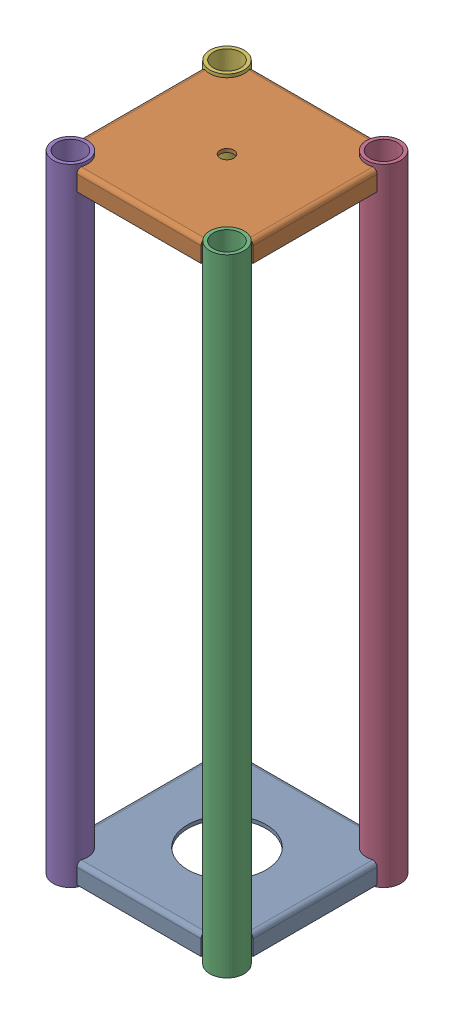
SolidWorks assembly GE-25202, configuration Default. Lengths in mm.
Overall size (185.8 609.6 185.8).
6 component instances, 3 part files, 17 mates.
Components (placement in the parent):
- GE-25202-01-1: GE-25202-01 [Default] at (0 22.225 0) size (171.42 19.05 171.42)
- GE-25202-02-1: GE-25202-02 [Default] at (0 606.425 0) size (171.42 19.05 171.42)
- GE-25202-03-1: GE-25202-03 [Default] at (76.2 0 76.2) size (33.4 609.6 33.4)
- GE-25202-03-2: GE-25202-03 [Default] at (76.2 0 -76.2) size (33.4 609.6 33.4)
- GE-25202-03-3: GE-25202-03 [Default] at (-76.2 0 76.2) size (33.4 609.6 33.4)
- GE-25202-03-4: GE-25202-03 [Default] at (-76.2 0 -76.2) size (33.4 609.6 33.4)
Mates (geometry in assembly coordinates):
- Coincident1: coincident aligned: plane of shortie_m6-01-1 through (0 22.225 0) normal (0 0 1)
- Coincident2: coincident aligned: plane of shortie_m6-01-1 through (0 22.225 0) normal (1 0 0)
- Coincident3: coincident aligned: plane of shortie_m6-01-1 through (0 22.225 85.7123) normal (0 0 1); plane of shortie_m6-02-1 through (0 606.425 85.7123) normal (0 0 1)
- Coincident4: coincident aligned: plane of shortie_m6-01-1 through (85.7123 22.225 0) normal (1 0 0); plane of shortie_m6-02-1 through (85.7123 606.425 0) normal (1 0 0)
- Distance1: distance = 603.25 mm anti-aligned: plane of shortie_m6-02-1 through (76.2 606.425 76.2) normal (0 1 0); plane of shortie_m6-01-1 through (-60.3828 3.175 85.7123) normal (0 -1 0)
- Concentric1: concentric anti-aligned: cylinder of shortie_m6-02-1 through (-76.2 603.0087 76.2) axis (0 1 0) radius 16.7005; cylinder of shortie_m6-03-3 through (-76.2 609.6 76.2) axis (0 -1 0) radius 16.7005
- Distance2: distance = 3.175 mm aligned: plane of shortie_m6-03-3 through (-76.2 609.6 76.2) normal (0 1 0); plane of shortie_m6-02-1 through (76.2 606.425 76.2) normal (0 1 0)
- Concentric2: concentric anti-aligned: cylinder of shortie_m6-02-1 through (76.2 603.0087 76.2) axis (0 1 0) radius 16.7005; cylinder of shortie_m6-03-1 through (76.2 609.6 76.2) axis (0 -1 0) radius 16.7005
- Coincident7: coincident aligned: plane of shortie_m6-03-1 through (76.2 609.6 76.2) normal (0 1 0); plane of shortie_m6-03-3 through (-76.2 609.6 76.2) normal (0 1 0)
- Concentric3: concentric anti-aligned: cylinder of shortie_m6-02-1 through (76.2 603.0087 -76.2) axis (0 1 0) radius 16.7005; cylinder of shortie_m6-03-2 through (76.2 609.6 -76.2) axis (0 -1 0) radius 16.7005
- Coincident8: coincident aligned: plane of shortie_m6-03-1 through (76.2 609.6 76.2) normal (0 1 0); plane of shortie_m6-03-2 through (76.2 609.6 -76.2) normal (0 1 0)
- Concentric4: concentric anti-aligned: line of shortie_m6-02-1 through (-76.2 603.0087 -76.2) axis (0 1 0); axis of shortie_m6-03-4 through (-76.2 609.6 -76.2) axis (0 -1 0)
- Coincident9: coincident aligned: plane of shortie_m6-03-2 through (76.2 609.6 -76.2) normal (0 1 0); plane of shortie_m6-03-4 through (-76.2 609.6 -76.2) normal (0 1 0)
- Coincident10: coincident anti-aligned: plane of shortie_m6-03-1 through (76.2 0 76.2) normal (0 -1 0)
- Coincident11: coincident anti-aligned: plane of shortie_m6-03-3 through (-76.2 0 76.2) normal (0 -1 0)
- Coincident12: coincident anti-aligned: plane of shortie_m6-03-4 through (-76.2 0 -76.2) normal (0 -1 0)
- Coincident13: coincident anti-aligned: plane of shortie_m6-03-2 through (76.2 0 -76.2) normal (0 -1 0)
